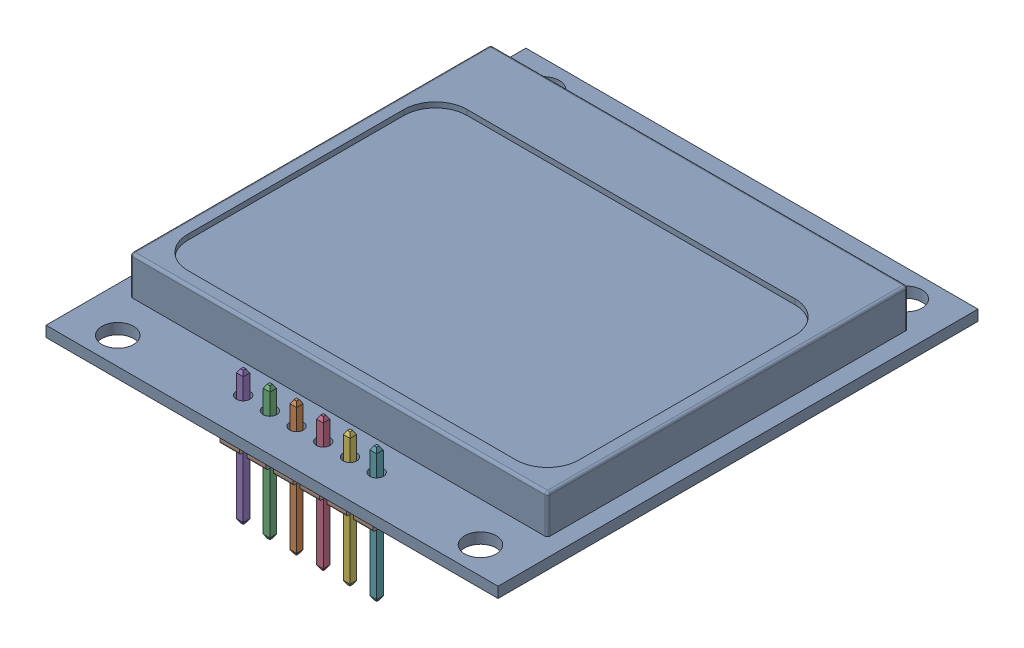
SolidWorks assembly Nokia_5110-3310_LCD_asm, configuration Default. Lengths in mm.
Overall size (43 14.16 45.65).
2 component instances, 2 part files, 0 mates.
Components (placement in the parent):
- Nokia_5110-3310_LCD_breakout-1: Nokia_5110-3310_LCD_breakout [Default] at (-5.0727 0 -2.7886) x (-1 0 0) z (0 0 -1) size (43 4.67 45.65)
- Pin Header 1x6 TH Pitch 2.54mm-1: Pin Header 1x6 TH Pitch 2.54mm [Default] at (1.2773 -1.0146 16.4339) x (-1 0 0) z (0 -1 0) size (15.24 2.54 12.7)
